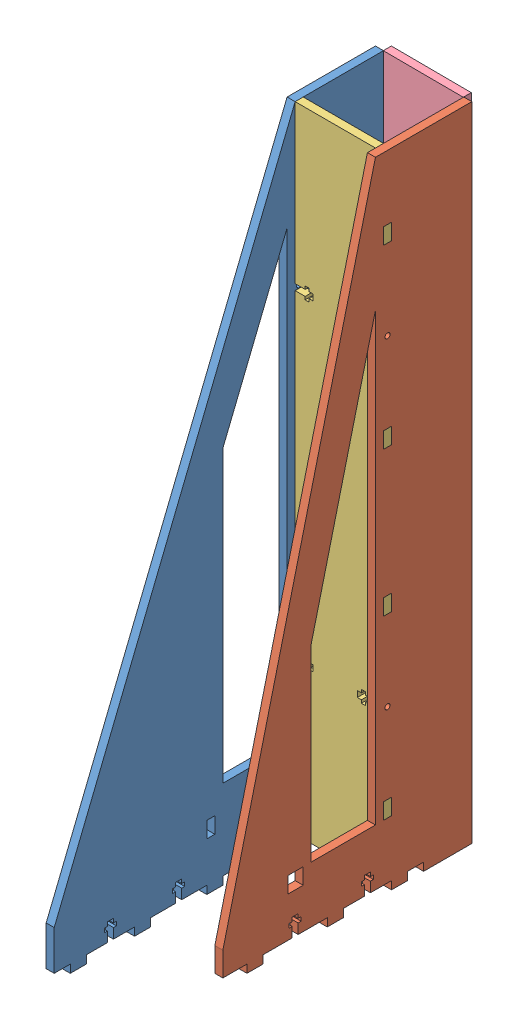
SolidWorks assembly ContainerUp, configuration Default. Lengths in mm.
Overall size (101.6 508 280.05).
16 component instances, 7 part files, 44 mates.
Components (placement in the parent):
- ContainerTop-1: ContainerTop [Default] at (-66.1507 223.3546 509.2001) size (6.35 508 260.35)
- ContainerBottom-1: ContainerBottom [Default] at (3.6993 223.3546 445.7001) x (0 0 -1) z (1 0 0) size (196.85 508 6.35)
- ContainerLeft-1: ContainerLeft [Default] at (-66.1507 223.3546 312.3501) size (76.2 501.65 6.35)
- ContainerRight-1: ContainerRight [Default] at (-59.8461 223.3546 242.5754) x (-0.004755 0 0.999989) z (-0.999989 0 -0.004755) size (6.35 508 63.5)
- DoorJam-1: DoorJam [Default] at (-59.8007 591.6546 274.2501) x (0 0 -1) z (1 0 0) size (45.09 6.35 19.68)
- DoorJam-2: DoorJam [Default] at (-59.8007 356.7046 274.2501) x (0 0 -1) z (1 0 0) size (45.09 6.35 19.68)
- DoorJam-3: DoorJam [Default] at (-59.8007 604.3546 274.2501) x (0 0 -1) z (1 0 0) size (45.09 6.35 19.68)
- DoorJam-4: DoorJam [Default] at (-59.8007 344.0046 274.2501) x (0 0 -1) z (1 0 0) size (45.09 6.35 19.68)
- DoorJam-5: DoorJam [Default] at (-34.4765 617.0546 249.0461) x (-0.999989 0 -0.004755) z (-0.004755 0 0.999989) size (45.09 6.35 19.68)
- DoorJam-6: DoorJam [Default] at (-34.4765 604.3546 249.0461) x (-0.999989 0 -0.004755) z (-0.004755 0 0.999989) size (45.09 6.35 19.68)
- DoorJam-7: DoorJam [Default] at (-34.4765 471.0046 249.0461) x (-0.999989 0 -0.004755) z (-0.004755 0 0.999989) size (45.09 6.35 19.68)
- DoorJam-8: DoorJam [Default] at (-34.4765 356.7046 249.0461) x (-0.999989 0 -0.004755) z (-0.004755 0 0.999989) size (45.09 6.35 19.68)
- DoorJam-9: DoorJam [Default] at (-34.4765 344.0046 249.0461) x (-0.999989 0 -0.004755) z (-0.004755 0 0.999989) size (45.09 6.35 19.68)
- DoorJam-10: DoorJam [Default] at (-34.4765 483.7046 249.0461) x (-0.999989 0 -0.004755) z (-0.004755 0 0.999989) size (45.09 6.35 19.68)
- pololu_plastic_180_flat-1: pololu_plastic_180_flat [Default] at (-78.5507 452.5046 248.4602) x (0 0 1) z (0 1 0) size (54.5 24.8 23.5)
- DoorServoHolder-1: DoorServoHolder [Default] at (-66.1507 445.6046 248.8501) x (0 0 1) z (1 0 0) size (50.8 6.35 31.75)
Mates (geometry in assembly coordinates):
- Coincident1: coincident anti-aligned: plane of ContainerTop-1 through (-59.8007 223.3546 509.2001) normal (1 0 0); plane of ContainerLeft-1 through (-59.8007 426.5546 318.7001) normal (-1 0 0)
- Coincident2: coincident aligned: plane of ContainerTop-1 through (-59.8007 731.3546 509.2001) normal (0 1 0); plane of ContainerLeft-1 through (-59.8007 731.3546 318.7001) normal (0 1 0)
- Coincident3: coincident anti-aligned: plane of ContainerTop-1 through (-66.1507 680.5546 318.7001) normal (0 0 -1); plane of ContainerLeft-1 through (-66.1507 223.3546 318.7001) normal (0 0 1)
- Coincident4: coincident anti-aligned: plane of ContainerBottom-1 through (3.6993 223.3546 445.7001) normal (-1 0 0); plane of ContainerLeft-1 through (3.6993 680.5546 318.7001) normal (1 0 0)
- Coincident5: coincident anti-aligned: plane of ContainerBottom-1 through (3.6993 667.8546 312.3501) normal (0 0 1); plane of ContainerLeft-1 through (-66.1507 223.3546 312.3501) normal (0 0 -1)
- Coincident6: coincident anti-aligned: plane of ContainerBottom-1 through (3.6993 680.5546 318.7001) normal (0 -1 0); plane of ContainerLeft-1 through (10.0493 680.5546 318.7001) normal (0 1 0)
- Coincident7: coincident aligned: plane of ContainerTop-1 through (-59.8007 731.3546 509.2001) normal (0 1 0); plane of ContainerRight-1 through (-59.8763 731.3546 248.9253) normal (0 1 0)
- Coincident9: coincident anti-aligned: plane of ContainerTop-1 through (-66.1507 604.3546 274.2501) normal (0 0 -1); plane of DoorJam-3 through (-59.8007 610.7046 274.2501) normal (0 0 1)
- Coincident10: coincident anti-aligned: plane of ContainerTop-1 through (-66.1507 598.0046 274.2501) normal (0 0 -1); plane of DoorJam-1 through (-59.8007 598.0046 274.2501) normal (0 0 1)
- Coincident11: coincident anti-aligned: plane of ContainerTop-1 through (-66.1507 356.7046 274.2501) normal (0 0 -1); plane of DoorJam-2 through (-59.8007 363.0546 274.2501) normal (0 0 1)
- Coincident12: coincident anti-aligned: plane of ContainerTop-1 through (-66.1507 350.3546 274.2501) normal (0 0 -1); plane of DoorJam-4 through (-59.8007 350.3546 274.2501) normal (0 0 1)
- Coincident13: coincident anti-aligned: plane of ContainerTop-1 through (-66.1507 610.7046 261.5501) normal (0 -1 0); plane of DoorJam-3 through (-68.6907 610.7046 264.0901) normal (0 1 0)
- Coincident14: coincident anti-aligned: plane of ContainerTop-1 through (-66.1507 598.0046 261.5501) normal (0 -1 0); plane of DoorJam-1 through (-68.6907 598.0046 264.0901) normal (0 1 0)
- Coincident15: coincident anti-aligned: plane of ContainerTop-1 through (-66.1507 363.0546 261.5501) normal (0 -1 0); plane of DoorJam-2 through (-68.6907 363.0546 264.0901) normal (0 1 0)
- Coincident16: coincident anti-aligned: plane of ContainerTop-1 through (-66.1507 350.3546 261.5501) normal (0 -1 0); plane of DoorJam-4 through (-68.6907 350.3546 264.0901) normal (0 1 0)
- Coincident17: coincident aligned: plane of ContainerTop-1 through (-59.8007 223.3546 509.2001) normal (1 0 0); plane of DoorJam-2 through (-59.8007 363.0546 274.2501) normal (1 0 0)
- Coincident18: coincident aligned: plane of ContainerTop-1 through (-59.8007 223.3546 509.2001) normal (1 0 0); plane of DoorJam-4 through (-59.8007 350.3546 274.2501) normal (1 0 0)
- Coincident19: coincident aligned: plane of ContainerTop-1 through (-59.8007 223.3546 509.2001) normal (1 0 0); plane of DoorJam-3 through (-59.8007 610.7046 274.2501) normal (1 0 0)
- Coincident20: coincident aligned: plane of ContainerTop-1 through (-59.8007 223.3546 509.2001) normal (1 0 0); plane of DoorJam-1 through (-59.8007 598.0046 274.2501) normal (1 0 0)
- Coincident21: coincident anti-aligned: plane of ContainerRight-1 through (-34.4765 223.3546 249.0461) normal (-0.999989 0 -0.004755); plane of DoorJam-5 through (-34.4765 610.7046 249.0461) normal (0.999989 0 0.004755)
- Coincident22: coincident anti-aligned: plane of ContainerRight-1 through (-34.4765 223.3546 249.0461) normal (-0.999989 0 -0.004755); plane of DoorJam-6 through (-34.4765 598.0046 249.0461) normal (0.999989 0 0.004755)
- Coincident23: coincident anti-aligned: plane of ContainerRight-1 through (-34.4765 223.3546 249.0461) normal (-0.999989 0 -0.004755); plane of DoorJam-10 through (-34.4765 477.3546 249.0461) normal (0.999989 0 0.004755)
- Coincident24: coincident anti-aligned: plane of ContainerRight-1 through (-34.4765 223.3546 249.0461) normal (-0.999989 0 -0.004755); plane of DoorJam-8 through (-34.4765 350.3546 249.0461) normal (0.999989 0 0.004755)
- Coincident25: coincident anti-aligned: plane of ContainerRight-1 through (-34.4765 223.3546 249.0461) normal (-0.999989 0 -0.004755); plane of DoorJam-9 through (-34.4765 337.6546 249.0461) normal (0.999989 0 0.004755)
- Coincident26: coincident anti-aligned: plane of ContainerRight-1 through (-34.4765 223.3546 249.0461) normal (-0.999989 0 -0.004755); plane of DoorJam-7 through (-34.4765 464.6546 249.0461) normal (0.999989 0 0.004755)
- Coincident27: coincident anti-aligned: plane of ContainerRight-1 through (-59.8763 617.0546 248.9253) normal (0 -1 0); plane of DoorJam-5 through (-44.5942 617.0546 240.1079) normal (0 1 0)
- Coincident28: coincident anti-aligned: plane of ContainerRight-1 through (-59.8763 604.3546 248.9253) normal (0 -1 0); plane of DoorJam-6 through (-44.5942 604.3546 240.1079) normal (0 1 0)
- Coincident29: coincident anti-aligned: plane of ContainerRight-1 through (-59.8763 483.7046 248.9253) normal (0 -1 0); plane of DoorJam-10 through (-44.5942 483.7046 240.1079) normal (0 1 0)
- Coincident30: coincident anti-aligned: plane of ContainerRight-1 through (-59.8763 471.0046 248.9253) normal (0 -1 0); plane of DoorJam-7 through (-44.5942 471.0046 240.1079) normal (0 1 0)
- Coincident31: coincident anti-aligned: plane of ContainerRight-1 through (-59.8763 356.7046 248.9253) normal (0 -1 0); plane of DoorJam-8 through (-44.5942 356.7046 240.1079) normal (0 1 0)
- Coincident32: coincident anti-aligned: plane of ContainerRight-1 through (-59.8763 344.0046 248.9253) normal (0 -1 0); plane of DoorJam-9 through (-44.5942 344.0046 240.1079) normal (0 1 0)
- Coincident33: coincident aligned: plane of ContainerRight-1 through (-59.8763 223.3546 248.9253) normal (-0.004755 0 0.999989); plane of DoorJam-9 through (-34.4765 337.6546 249.0461) normal (-0.004755 0 0.999989)
- Coincident34: coincident aligned: plane of ContainerRight-1 through (-59.8763 223.3546 248.9253) normal (-0.004755 0 0.999989); plane of DoorJam-8 through (-34.4765 350.3546 249.0461) normal (-0.004755 0 0.999989)
- Coincident35: coincident aligned: plane of ContainerRight-1 through (-59.8763 223.3546 248.9253) normal (-0.004755 0 0.999989); plane of DoorJam-7 through (-34.4765 464.6546 249.0461) normal (-0.004755 0 0.999989)
- Coincident36: coincident aligned: plane of ContainerRight-1 through (-59.8763 223.3546 248.9253) normal (-0.004755 0 0.999989); plane of DoorJam-10 through (-34.4765 477.3546 249.0461) normal (-0.004755 0 0.999989)
- Coincident37: coincident aligned: plane of ContainerRight-1 through (-59.8763 223.3546 248.9253) normal (-0.004755 0 0.999989); plane of DoorJam-6 through (-34.4765 598.0046 249.0461) normal (-0.004755 0 0.999989)
- Coincident39: coincident aligned: plane of ContainerRight-1 through (-59.8763 223.3546 248.9253) normal (-0.004755 0 0.999989); plane of DoorJam-5 through (-34.4765 610.7046 249.0461) normal (-0.004755 0 0.999989)
- Coincident41: coincident aligned: plane of ContainerTop-1 through (-59.8007 731.3546 509.2001) normal (0 1 0); plane of ContainerRight-1 through (-59.8763 731.3546 248.9253) normal (0 1 0)
- Coincident42: coincident anti-aligned: circle of DoorJam-3; circle of DoorJam-5
- Coincident43: coincident anti-aligned: plane of ContainerTop-1 through (-66.1507 223.3546 509.2001) normal (-1 0 0); plane of pololu_plastic_180_flat-1 through (-66.1507 459.4046 279.9602) normal (1 0 0)
- Coincident44: coincident anti-aligned: plane of ContainerTop-1 through (-66.1507 223.3546 509.2001) normal (-1 0 0); plane of DoorServoHolder-1 through (-66.1507 439.2546 248.8501) normal (1 0 0)
- Coincident45: coincident anti-aligned: plane of ContainerTop-1 through (-66.1507 445.6046 261.5501) normal (0 -1 0); plane of DoorServoHolder-1 through (-66.1507 445.6046 248.8501) normal (0 1 0)
- Coincident46: coincident anti-aligned: plane of ContainerTop-1 through (-66.1507 439.2546 261.5501) normal (0 0 1); plane of DoorServoHolder-1 through (-66.1507 439.2546 261.5501) normal (0 0 -1)
- Coincident47: coincident anti-aligned: plane of pololu_plastic_180_flat-1 through (-78.5507 445.6046 248.4602) normal (0 -1 0); plane of DoorServoHolder-1 through (-66.1507 445.6046 248.8501) normal (0 1 0)
